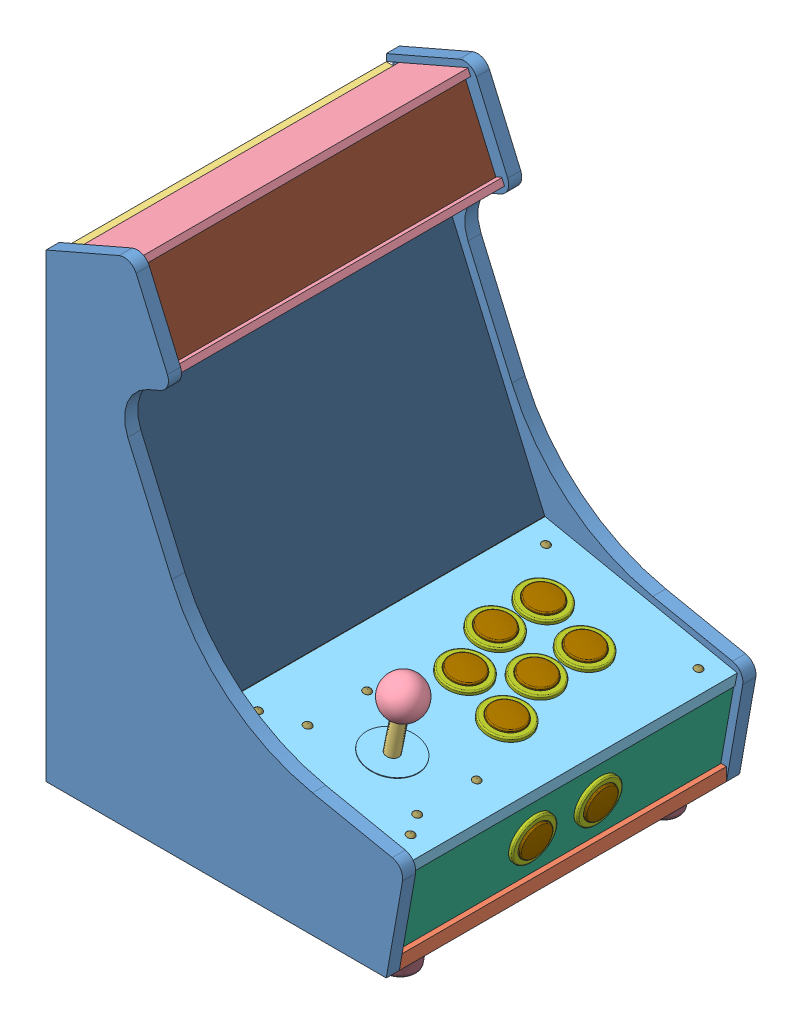
SolidWorks assembly BarTop - Ensamblaje Base, configuration Predeterminado. Lengths in mm.
Overall size (282.71 397.01 270).
106 component instances, 38 part files, 132 mates.
Components (placement in the parent):
- BarTop - Perfil v1.0-1: BarTop - Perfil v1.0 [Derecha] at (-132.2405 -179.0769 376.8453) size (272.57 376.85 10)
- BarTop - Perfil v1.0-2: BarTop - Perfil v1.0 [Izquierda] at (-132.2405 -179.0769 636.8453) size (272.57 376.85 10)
- BarTop - Base v1.0-2: BarTop - Base v1.0 [Predeterminado] at (-2.2405 -179.0769 511.8453) x (0 0 -1) z (1 0 0) size (250 10 260)
- BarTop - Trasera v1.0-1: BarTop - Trasera v1.0 [Predeterminado] at (-132.2405 -0.8669 511.8453) x (0 0 -1) z (1 0 0) size (250 336.42 10)
- BarTop - Top01 v1.0-1: BarTop - Top01 v1.0 [Top] at (-99.2135 181.6383 516.6589) x (0.917317 0.398157 0) z (0.398157 -0.917317 0) size (57.92 260 5)
- BarTop - Top01 v1.0-2: BarTop - Top01 v1.0 [Botton] at (-73.3333 122.0127 516.6589) x (0.917317 0.398157 0) z (0.398157 -0.917317 0) size (76.43 260 5)
- BarTop - Top Mando v1.0-1: BarTop - Top Mando v1.0 [Predeterminado] at (60.6117 -97.8004 511.8453) x (0 0 -1) z (0.979796 -0.2 0) size (250 10 150)
- BarTop - Botton Mando v1.0-1: BarTop - Botton Mando v1.0 [Predeterminado] at (127.5697 -145.6008 511.6606) x (0 0 -1) z (-0.984808 0.173648 0) size (260 61.41 5)
- BarTop - Escuadra 70 v1.0-2: BarTop - Escuadra 70 v1.0 [Predeterminado] at (-122.2405 -58.1616 386.8453) x (0 1 0) z (0 0 -1) size (30 12.5 15)
- BarTop - Escuadra 70 v1.0-5: BarTop - Escuadra 70 v1.0 [Predeterminado] at (-122.2405 51.8384 636.8453) x (0 -1 0) z (0 0 1) size (30 12.5 15)
- BarTop - Escuadra Mando v1.0-1: BarTop - Escuadra Mando v1.0 [Predeterminado] at (5.3678 -91.6269 386.8453) x (0.979796 -0.2 0) z (0 0 1) size (39.28 37.5 27.5)
- BarTop - Marco LCD 9.7 v1.0-1: BarTop - Marco LCD 9.7 v1.0 [Predeterminado] at (-72.642 8.6662 511.8453) x (0 0 -1) z (0.917317 0.398157 0) size (259 228.59 23.87)
- BarTop - Escuadra Mando 2 v1.0-1: BarTop - Escuadra Mando 2 v1.0 [Predeterminado] at (93.082 -133.1747 386.8453) x (1 0.000655 0) z (0 0 1) size (39.11 32.51 27.42)
- BarTop - Escuadra Base 1 v1.0-1: BarTop - Escuadra Base 1 v1.0 [Predeterminado] at (118.2897 -169.0769 386.8453) size (39.34 24.62 27.07)
- BarTop - Escuadra Base 2 v1.0-1: BarTop - Escuadra Base 2 v1.0 [Predeterminado] at (-122.2405 -169.0769 386.8453) size (30 30 32.5)
- BarTop - Escuadra Top 1 v1.0-1: BarTop - Escuadra Top 1 v1.0 [Predeterminado] at (-109.3009 157.0815 386.8453) size (27.52 41.94 27.46)
- BarTop - Stand LedStrip v1.0-1: BarTop - Stand LedStrip v1.0 [Predeterminado] at (-99.3061 110.7393 511.8453) x (0 0 -1) z (0.917317 0.398157 0) size (220 35 15)
- LCD iPad-5 - 9,7' - SN-LP097QX2-1: LCD iPad-5 - 9,7' - SN-LP097QX2 [Pacman] at (-80.3476 20.3914 510.4922) x (0 0 -1) z (0.917317 0.398157 0) size (217 160 2.4)
- Joystick Sanwa -Mod JLF-TP-8YT-W 1-1: Joystick Sanwa -Mod JLF-TP-8YT-W 1 [Predeterminado] at (69.2639 -95.1778 584.9479) x (0.979796 -0.2 0) z (-0.2 -0.979796 0) size (100 66.68 104.46)
  - SANWA_JOYSTICK_3-1: SANWA_JOYSTICK_3 [Predeterminado] at origin size (100 60 1.5)
  - SSANWA_JOYSTICK_6-1: SSANWA_JOYSTICK_6 [Predeterminado] at origin size (66 60 30)
  - SANWA_JOYSTICK_2-1: SANWA_JOYSTICK_2 [Predeterminado] x (1 0 0) z (0 1 0) size (39.99 20.68 39.98)
  - SANWA_JOYSTICK_5-1: SANWA_JOYSTICK_5 [Predeterminado] at (0 0 12.592) x (1 0 0) z (0 0 -1) size (66.1 66.68 17.11)
  - GT-Y-1: GT-Y [Predeterminado] at (0 0 27.552) size (60 60 10)
  - SANWA_JOYSTICK_0-1: SANWA_JOYSTICK_0 [Predeterminado] at (0 0 7.5029) x (0.996812 -0.079782 0) z (0.079782 0.996812 0) size (10 85 10)
  - BALL-1: BALL [Predeterminado] at (0 0 -47.9539) x (0.999996 -0.002826 0) z (0.002826 0.999996 0) size (30 30 30)
  - DUSTER-1: DUSTER [Predeterminado] at (0 0 -6.2) x (-1 0 0) z (0 0 1) size (40 40 0.5)
  - E-1: E [Predeterminado] at (0 0 39.0029) x (0.999996 -0.002826 0) z (0.002826 0.999996 0) size (5.88 1.1 10)
- sanwa_button_00_asm_6-1: sanwa_button_00_asm_6 [Predeterminado] at (46.9421 -100.1132 509.0802) x (0.979796 -0.2 0) z (0 0 1) size (34 37.41 37.09)
  - sanwa_button_00_11-1: sanwa_button_00_11 [Predeterminado] at origin size (34 22.2 37.09)
  - black_00_3-1: black_00_3 [Predeterminado] at (0 5 0) x (-1 0 0) z (0 0 1) size (14 26.9 14)
  - sanwa_button_02_8-1: sanwa_button_02_8 [Predeterminado] at (0 17 0) x (0 0 -1) z (1 0 0) size (25 13.51 28.68)
- sanwa_button_00_asm_6-3: sanwa_button_00_asm_6 [Predeterminado] at (32.919 -97.2507 472.0638) x (0.979796 -0.2 0) z (0 0 1) size (34 37.41 37.09)
  - sanwa_button_00_11-1: sanwa_button_00_11 [Predeterminado] at origin size (34 22.2 37.09)
  - black_00_3-1: black_00_3 [Predeterminado] at (0 5 0) x (-1 0 0) z (0 0 1) size (14 26.9 14)
  - sanwa_button_02_8-1: sanwa_button_02_8 [Predeterminado] at (0 17 0) x (0 0 -1) z (1 0 0) size (25 13.51 28.68)
- sanwa_button_00_asm_6-4: sanwa_button_00_asm_6 [Predeterminado] at (32.919 -97.2507 435.3274) x (0.979796 -0.2 0) z (0 0 1) size (34 37.41 37.09)
  - sanwa_button_00_11-1: sanwa_button_00_11 [Predeterminado] at origin size (34 22.2 37.09)
  - black_00_3-1: black_00_3 [Predeterminado] at (0 5 0) x (-1 0 0) z (0 0 1) size (14 26.9 14)
  - sanwa_button_02_8-1: sanwa_button_02_8 [Predeterminado] at (0 17 0) x (0 0 -1) z (1 0 0) size (25 13.51 28.68)
- sanwa_button_00_asm_6-5: sanwa_button_00_asm_6 [Predeterminado] at (85.9469 -108.075 516.2161) x (0.979796 -0.2 0) z (0 0 1) size (34 37.41 37.09)
  - sanwa_button_00_11-1: sanwa_button_00_11 [Predeterminado] at origin size (34 22.2 37.09)
  - black_00_3-1: black_00_3 [Predeterminado] at (0 5 0) x (-1 0 0) z (0 0 1) size (14 26.9 14)
  - sanwa_button_02_8-1: sanwa_button_02_8 [Predeterminado] at (0 17 0) x (0 0 -1) z (1 0 0) size (25 13.51 28.68)
- sanwa_button_00_asm_6-6: sanwa_button_00_asm_6 [Predeterminado] at (72.2638 -105.2819 479.7317) x (0.979796 -0.2 0) z (0 0 1) size (34 37.41 37.09)
  - sanwa_button_00_11-1: sanwa_button_00_11 [Predeterminado] at origin size (34 22.2 37.09)
  - black_00_3-1: black_00_3 [Predeterminado] at (0 5 0) x (-1 0 0) z (0 0 1) size (14 26.9 14)
  - sanwa_button_02_8-1: sanwa_button_02_8 [Predeterminado] at (0 17 0) x (0 0 -1) z (1 0 0) size (25 13.51 28.68)
- sanwa_button_00_asm_6-7: sanwa_button_00_asm_6 [Predeterminado] at (72.2638 -105.2819 442.994) x (0.979796 -0.2 0) z (0 0 1) size (34 37.41 37.09)
  - sanwa_button_00_11-1: sanwa_button_00_11 [Predeterminado] at origin size (34 22.2 37.09)
  - black_00_3-1: black_00_3 [Predeterminado] at (0 5 0) x (-1 0 0) z (0 0 1) size (14 26.9 14)
  - sanwa_button_02_8-1: sanwa_button_02_8 [Predeterminado] at (0 17 0) x (0 0 -1) z (1 0 0) size (25 13.51 28.68)
- sanwa_button_00_asm_6-8: sanwa_button_00_asm_6 [Predeterminado] at (113.7095 -137.8242 586.8453) x (-0.173648 -0.984808 0) z (0 0 1) size (34 37.41 37.09) (hidden)
  - sanwa_button_00_11-1: sanwa_button_00_11 [Predeterminado] at origin size (34 22.2 37.09)
  - black_00_3-1: black_00_3 [Predeterminado] at (0 5 0) x (-1 0 0) z (0 0 1) size (14 26.9 14)
  - sanwa_button_02_8-1: sanwa_button_02_8 [Predeterminado] at (0 17 0) x (0 0 -1) z (1 0 0) size (25 13.51 28.68)
- sanwa_button_00_asm_6-9: sanwa_button_00_asm_6 [Predeterminado] at (113.7095 -137.8242 536.8453) x (-0.173648 -0.984808 0) z (0 0 1) size (34 37.41 37.09)
  - sanwa_button_00_11-1: sanwa_button_00_11 [Predeterminado] at origin size (34 22.2 37.09)
  - black_00_3-1: black_00_3 [Predeterminado] at (0 5 0) x (-1 0 0) z (0 0 1) size (14 26.9 14)
  - sanwa_button_02_8-1: sanwa_button_02_8 [Predeterminado] at (0 17 0) x (0 0 -1) z (1 0 0) size (25 13.51 28.68)
- sanwa_button_00_asm_6-10: sanwa_button_00_asm_6 [Predeterminado] at (113.7095 -137.8242 486.8453) x (-0.173648 -0.984808 0) z (0 0 1) size (34 37.41 37.09)
  - sanwa_button_00_11-1: sanwa_button_00_11 [Predeterminado] at origin size (34 22.2 37.09)
  - black_00_3-1: black_00_3 [Predeterminado] at (0 5 0) x (-1 0 0) z (0 0 1) size (14 26.9 14)
  - sanwa_button_02_8-1: sanwa_button_02_8 [Predeterminado] at (0 17 0) x (0 0 -1) z (1 0 0) size (25 13.51 28.68)
- sanwa_button_00_asm_6-11: sanwa_button_00_asm_6 [Predeterminado] at (113.7095 -137.8242 436.8453) x (-0.173648 -0.984808 0) z (0 0 1) size (34 37.41 37.09) (hidden)
  - sanwa_button_00_11-1: sanwa_button_00_11 [Predeterminado] at origin size (34 22.2 37.09)
  - black_00_3-1: black_00_3 [Predeterminado] at (0 5 0) x (-1 0 0) z (0 0 1) size (14 26.9 14)
  - sanwa_button_02_8-1: sanwa_button_02_8 [Predeterminado] at (0 17 0) x (0 0 -1) z (1 0 0) size (25 13.51 28.68)
- BarTop - Vidrio v1.0-1: BarTop - Vidrio v1.0 [Predeterminado] at (-52.461 17.4256 511.8453) x (0 0 -1) z (0.917317 0.398157 0) size (250 198.5 2)
- BarTop - Marquesina v1.0-1: BarTop - Marquesina v1.0 [Predeterminado] at (-62.2378 159.5328 511.8453) x (0 0 -1) z (0.917317 0.398157 0) size (260 64 2)
- Tornillo cabeza redonda M3x16-1: Tornillo cabeza redonda M3x16 [Predeterminado] at (109.0608 -113.8137 562.1979) x (0.979796 -0.2 0) z (0 0 1) size (6 17.5 6)
- Tornillo cabeza redonda M3x16-2: Tornillo cabeza redonda M3x16 [Predeterminado] at (109.0608 -113.8137 607.6979) x (0.979796 -0.2 0) z (0 0 1) size (6 17.5 6)
- Tornillo cabeza redonda M3x16-5: Tornillo cabeza redonda M3x16 [Predeterminado] at (118.1994 -115.6791 621.8453) x (0.979796 -0.2 0) z (0 0 1) size (6 17.5 6)
- Tornillo cabeza redonda M3x16-6: Tornillo cabeza redonda M3x16 [Predeterminado] at (118.1994 -115.6791 401.8453) x (-0.297762 0.06078 0.952703) z (-0.933455 0.190541 -0.303902) size (6 17.5 6)
- Tornillo cabeza redonda M3x16-7: Tornillo cabeza redonda M3x16 [Predeterminado] at (25.347 -96.7257 562.1979) x (0.979796 -0.2 0) z (0 0 1) size (6 17.5 6)
- Tornillo cabeza redonda M3x16-9: Tornillo cabeza redonda M3x16 [Predeterminado] at (1.6037 -91.8791 621.8453) x (0.979796 -0.2 0) z (0 0 1) size (6 17.5 6)
- Tornillo cabeza redonda M3x16-10: Tornillo cabeza redonda M3x16 [Predeterminado] at (1.6037 -91.8791 401.8453) x (0.979796 -0.2 0) z (0 0 1) size (6 17.5 6)
- Tornillo cabeza redonda M3x16-11: Tornillo cabeza redonda M3x16 [Predeterminado] at (25.347 -96.7257 607.6979) x (0.979796 -0.2 0) z (0 0 1) size (6 17.5 6)
- Patas de Goma-1: Patas de Goma [Predeterminado] at (104.9763 -199.0769 613.3031) size (30 20.17 30)
- Patas de Goma-2: Patas de Goma [Predeterminado] at (101.674 -199.0769 408.8359) size (30 20.17 30)
- Patas de Goma-3: Patas de Goma [Predeterminado] at (-108.4119 -199.0769 409.4186) size (30 20.17 30)
- Patas de Goma-4: Patas de Goma [Predeterminado] at (-109.83 -199.0769 613.7143) size (30 20.17 30)
- Inserto M4 FXSLB - Fixor.es-1: Inserto M4 FXSLB - Fixor.es [Predeterminado] at (108.2897 -169.0769 396.8453) x (0.999794 0 0.02028) z (0.02028 0 -0.999794) size (6.31 5.03 6.3)
- Inserto M4 FXSLB - Fixor.es-2: Inserto M4 FXSLB - Fixor.es [Predeterminado] at (-112.2405 -169.0769 396.8453) x (1 0 0) z (0 0 -1) size (6.31 5.03 6.3)
- Inserto M4 FXSLB - Fixor.es-3: Inserto M4 FXSLB - Fixor.es [Predeterminado] at (108.2897 -169.0769 626.8453) x (1 0 0) z (0 0 -1) size (6.31 5.03 6.3)
- Inserto M4 FXSLB - Fixor.es-4: Inserto M4 FXSLB - Fixor.es [Predeterminado] at (-112.2405 -169.0769 626.8453) x (1 0 0) z (0 0 -1) size (6.31 5.03 6.3)
- Inserto M4 FXSLB - Fixor.es-5: Inserto M4 FXSLB - Fixor.es [Predeterminado] at (-122.2405 -159.0769 626.8453) x (0 1 0) z (0 0 1) size (6.31 5.03 6.3)
- Inserto M4 FXSLB - Fixor.es-6: Inserto M4 FXSLB - Fixor.es [Predeterminado] at (-122.2405 -159.0769 396.8453) x (0 1 0) z (0 0 1) size (6.31 5.03 6.3)
- Inserto M4 FXSLB - Fixor.es-7: Inserto M4 FXSLB - Fixor.es [Predeterminado] at (-122.2405 -3.1616 393.0953) x (0 1 0) z (0 0 1) size (6.31 5.03 6.3)
- Inserto M4 FXSLB - Fixor.es-8: Inserto M4 FXSLB - Fixor.es [Predeterminado] at (-122.2405 -3.1616 630.5953) x (0 1 0) z (0 0 1) size (6.31 5.03 6.3)
- Inserto M4 FXSLB - Fixor.es-9: Inserto M4 FXSLB - Fixor.es [Predeterminado] at (-102.0686 104.0896 446.8453) x (0.917317 0.398157 0) z (0 0 1) size (6.31 5.03 6.3)
- Inserto M4 FXSLB - Fixor.es-10: Inserto M4 FXSLB - Fixor.es [Predeterminado] at (-102.0686 104.0896 576.8453) x (0.917317 0.398157 0) z (0 0 1) size (6.31 5.03 6.3)
- Inserto M4 FXSLB - Fixor.es-11: Inserto M4 FXSLB - Fixor.es [Predeterminado] at (-122.2405 156.1929 626.8453) x (0 1 0) z (0 0 1) size (6.31 5.03 6.3)
- Inserto M4 FXSLB - Fixor.es-13: Inserto M4 FXSLB - Fixor.es [Predeterminado] at (-122.2405 156.1929 396.8453) x (0 1 0) z (0 0 1) size (6.31 5.03 6.3)
- BarTop - Escuadra Top 1 v1.0-2: BarTop - Escuadra Top 1 v1.0 [SimetríaPredeterminado] at (-109.3009 157.0815 636.8453) size (27.52 41.94 27.46)
- BarTop - Escuadra Base 2 v1.0-3: BarTop - Escuadra Base 2 v1.0 [SimetríaPredeterminado] at (-122.2405 -169.0769 636.8453) size (30 30 32.5)
- BarTop - Escuadra Base 1 v1.0-3: BarTop - Escuadra Base 1 v1.0 [SimetríaPredeterminado] at (118.2897 -169.0769 636.8453) size (39.34 24.62 27.07)
- BarTop - Escuadra Mando 2 v1.0-3: BarTop - Escuadra Mando 2 v1.0 [SimetríaPredeterminado] at (93.082 -133.1747 636.8453) x (1 0.000655 0) z (0 0 1) size (39.11 32.51 27.42)
- BarTop - Escuadra Mando v1.0-2: BarTop - Escuadra Mando v1.0 [SimetríaPredeterminado] at (5.3678 -91.6269 636.8453) x (0.979796 -0.2 0) z (0 0 1) size (39.28 37.5 27.5)
- 40x40x10 fan cooler 5v sunon-1: 40x40x10 fan cooler 5v sunon [Default] at (-119.7405 -111.2889 521.9641) x (0 -1 0) z (0 0 1) size (51.62 11.06 51.62)
  - 40x40x10-1: 40x40x10 [Default] at (20 0 -20) x (0 0 -1) z (-1 0 0) size (44.65 10.7 40.2)
  - blade-1: blade [Default] at (20 -3.3 -20) x (-0.569127 0 0.822249) z (0.822249 0 0.569127) size (37.1 8.47 37.1)
- AC Power outlet connector-1: AC Power outlet connector [Default] at (-137.5405 -131.2889 552.1436) x (0 0 1) z (-1 0 0) size (50 22.4 26.9)
- Interruptor KCD4-201xx-1: Interruptor KCD4-201xx [Predeterminado] at (-134.2405 -130.8594 591.8776) x (0 -1 0) z (0 0 -1) size (31 26.34 25.5)
- BarTop - Soporte Enchufes Pz1 v1.0-1: BarTop - Soporte Enchufes Pz1 v1.0 [Predeterminado] at (-130.2405 -131.2268 543.4575) x (0 0 1) z (-1 0 0) size (141 56 10)
- BarTop - Soporte Enchufes Pz2 v1.0-1: BarTop - Soporte Enchufes Pz2 v1.0 [Predeterminado] at (-124.2405 -131.4003 543.4435) x (0 0 -1) z (1 0 0) size (135 50 19)
Mates (geometry in assembly coordinates):
- Coincidente1: coincident: point of BarTop - Perfil v1.0-1; point of BarTop - Base v1.0-2
- Coincidente2: coincident: point of BarTop - Perfil v1.0-2; point of BarTop - Base v1.0-2
- Coincidente3: coincident aligned: plane of BarTop - Base v1.0-2 through (-2.2405 -179.0769 511.8453) normal (0 -1 0); plane of BarTop - Perfil v1.0-2 through (-132.2405 -179.0769 646.8453) normal (0 -1 0)
- Coincidente4: coincident aligned: plane of BarTop - Base v1.0-2 through (-2.2405 -179.0769 511.8453) normal (0 -1 0); plane of BarTop - Perfil v1.0-1 through (-132.2405 -179.0769 386.8453) normal (0 -1 0)
- Coincidente10: coincident anti-aligned: plane of BarTop - Perfil v1.0-1 through (-132.2405 -179.0769 386.8453) normal (0 0 1); plane of BarTop - Escuadra 70 v1.0-2 through (-122.2405 11.8384 386.8453) normal (0 0 -1)
- Coincidente11: coincident anti-aligned: plane of BarTop - Trasera v1.0-1 through (-122.2405 -0.8669 511.8453) normal (1 0 0); plane of BarTop - Escuadra 70 v1.0-2 through (-122.2405 11.8384 386.8453) normal (-1 0 0)
- Coincidente17: coincident aligned: plane of BarTop - Perfil v1.0-1 through (-132.2405 172.7538 386.8453) normal (-1 0 0); plane of BarTop - Trasera v1.0-1 through (-132.2405 -0.8669 511.8453) normal (-1 0 0)
- Coincidente18: coincident anti-aligned: plane of BarTop - Perfil v1.0-2 through (-132.2405 -179.0769 636.8453) normal (0 0 -1); plane of BarTop - Trasera v1.0-1 through (-122.2405 167.3431 636.8453) normal (0 0 1)
- Coincidente19: coincident anti-aligned: plane of BarTop - Base v1.0-2 through (-2.2405 -169.0769 511.8453) normal (0 1 0); plane of BarTop - Trasera v1.0-1 through (-122.2405 -169.0769 636.8453) normal (0 -1 0)
- Paralelo1: parallel aligned: plane of BarTop - Perfil v1.0-2 through (-5.1037 -69.0769 646.8453) normal (0.917317 0.398157 0); plane of LCD iPad-5 - 9,7' - SN-LP097QX2-1 through (-78.3295 21.2674 510.4922) normal (0.917317 0.398157 0)
- Coincidente25: coincident anti-aligned: plane of BarTop - Perfil v1.0-2 through (-132.2405 -179.0769 636.8453) normal (0 0 -1); plane of BarTop - Base v1.0-2 through (-132.2405 -169.0769 636.8453) normal (0 0 1)
- Distancia2: distance = 5 mm aligned: plane of BarTop - Top01 v1.0-1 through (-99.2135 181.6383 516.6589) normal (-0.398157 0.917317 0); plane of BarTop - Perfil v1.0-2 through (-67.3412 200.9231 646.8453) normal (-0.398157 0.917317 0)
- Coincidente31: coincident anti-aligned: plane of BarTop - Top01 v1.0-1 through (-130.0663 162.7962 641.8453) normal (0 0 1); plane of BarTop - Perfil v1.0-2 through (-132.2405 -179.0769 641.8453) normal (0 0 -1)
- Coincidente124: coincident anti-aligned: plane of BarTop - Perfil v1.0-1 through (-67.6816 189.6559 381.8453) normal (-0.917317 -0.398157 0); plane of BarTop - Top01 v1.0-1 through (-67.7613 189.8394 641.8453) normal (0.917317 0.398157 0)
- Distancia3: distance = 5 mm aligned: plane of BarTop - Top Mando v1.0-1 through (62.6117 -88.0024 511.8453) normal (0.2 0.979796 0); plane of BarTop - Perfil v1.0-1 through (141.8656 -99.0769 386.8453) normal (0.2 0.979796 0)
- Coincidente35: coincident anti-aligned: plane of BarTop - Perfil v1.0-2 through (-132.2405 -179.0769 636.8453) normal (0 0 -1); plane of BarTop - Top Mando v1.0-1 through (-10.873 -73.0024 636.8453) normal (0 0 1)
- Distancia4: distance = 5 mm: line of BarTop - Top Mando v1.0-1 through (136.0963 -103.0024 636.8453) axis (0 0 -1); plane of BarTop - Perfil v1.0-2 through (127.7595 -179.0769 646.8453) normal (0.984808 -0.173648 0)
- Coincidente38: coincident anti-aligned: plane of BarTop - Top01 v1.0-2 through (-104.186 103.1706 641.8453) normal (0 0 1); plane of BarTop - Perfil v1.0-2 through (-132.2405 -179.0769 641.8453) normal (0 0 -1)
- Distancia5: distance = 5 mm aligned: plane of BarTop - Perfil v1.0-2 through (-81.7315 107.4662 646.8453) normal (0.398157 -0.917317 0); plane of BarTop - Top01 v1.0-2 through (-71.3425 117.4261 516.6589) normal (0.398157 -0.917317 0)
- Coincidente40: coincident aligned: plane of BarTop - Top01 v1.0-1 through (-67.7613 189.8394 641.8453) normal (0.917317 0.398157 0); plane of BarTop - Top01 v1.0-2 through (-41.881 130.2138 641.8453) normal (0.917317 0.398157 0)
- Distancia6: distance = 7 mm aligned: plane of BarTop - Vidrio v1.0-1 through (-50.6264 18.2219 511.8453) normal (0.917317 0.398157 0); plane of BarTop - Perfil v1.0-1 through (-5.1037 -69.0769 386.8453) normal (0.917317 0.398157 0)
- Coincidente42: coincident anti-aligned: plane of BarTop - Top01 v1.0-2 through (-71.3425 117.4261 516.6589) normal (0.398157 -0.917317 0); plane of BarTop - Vidrio v1.0-1 through (-90.1435 109.2657 636.8453) normal (-0.398157 0.917317 0)
- Coincidente44: coincident anti-aligned: plane of BarTop - Perfil v1.0-1 through (-132.2405 -179.0769 386.8453) normal (0 0 1); plane of BarTop - Vidrio v1.0-1 through (-90.1435 109.2657 386.8453) normal (0 0 -1)
- Coincidente45: coincident anti-aligned: plane of BarTop - Top01 v1.0-2 through (-47.6621 130.9749 381.8453) normal (-0.917317 -0.398157 0); plane of BarTop - Marquesina v1.0-1 through (-60.4031 160.3291 511.8453) normal (0.917317 0.398157 0)
- Coincidente46: coincident anti-aligned: plane of BarTop - Top01 v1.0-1 through (-98.0191 178.8864 516.6589) normal (0.398157 -0.917317 0); plane of BarTop - Marquesina v1.0-1 through (-73.1442 189.6832 641.8453) normal (-0.398157 0.917317 0)
- Coincidente47: coincident anti-aligned: plane of BarTop - Perfil v1.0-1 through (-132.2405 -179.0769 381.8453) normal (0 0 1); plane of BarTop - Marquesina v1.0-1 through (-73.1442 189.6832 381.8453) normal (0 0 -1)
- Coincidente48: coincident anti-aligned: plane of BarTop - Top Mando v1.0-1 through (60.6117 -97.8004 511.8453) normal (-0.2 -0.979796 0); plane of BarTop - Escuadra Mando v1.0-1 through (-12.873 -82.8004 411.8453) normal (0.2 0.979796 0)
- Coincidente49: coincident anti-aligned: plane of BarTop - Perfil v1.0-1 through (-132.2405 -179.0769 386.8453) normal (0 0 1); plane of BarTop - Escuadra Mando v1.0-1 through (-0.1313 -118.5668 386.8453) normal (0 0 -1)
- Concéntrica2: concentric aligned: cylinder of BarTop - Top Mando v1.0-1 through (2.8035 -86.0013 401.8453) axis (0.2 0.979796 0) radius 1.6; cylinder of BarTop - Escuadra Mando v1.0-1 through (-4.6956 -122.7392 401.8453) axis (0.2 0.979796 0) radius 2
- Distancia11: distance = 5 mm anti-aligned: plane of BarTop - Botton Mando v1.0-1 through (117.7918 -172.2597 641.8453) normal (0 0 1); plane of BarTop - Perfil v1.0-2 through (-132.2405 -179.0769 636.8453) normal (0 0 -1)
- Distancia12: distance = 6 mm aligned: plane of BarTop - Botton Mando v1.0-1 through (127.5697 -145.6008 511.6606) normal (0.984808 -0.173648 0); plane of BarTop - Perfil v1.0-2 through (127.7595 -179.0769 646.8453) normal (0.984808 -0.173648 0)
- Coincidente51: coincident: plane of BarTop - Top Mando v1.0-1 through (60.6117 -97.8004 511.8453) normal (-0.2 -0.979796 0); line of BarTop - Botton Mando v1.0-1 through (133.3791 -112.6539 641.8453) axis (0 0 -1)
- Coincidente52: coincident anti-aligned: plane of BarTop - Vidrio v1.0-1 through (-52.461 17.4256 511.8453) normal (-0.917317 -0.398157 0); plane of BarTop - Marco LCD 9.7 v1.0-1 through (-52.461 17.4256 511.8453) normal (0.917317 0.398157 0)
- Coincidente53: coincident aligned: plane of BarTop - Vidrio v1.0-1 through (-90.1435 109.2657 636.8453) normal (0 0 1); plane of BarTop - Marco LCD 9.7 v1.0-1 through (-91.9781 108.4693 636.8453) normal (0 0 1)
- Coincidente54: coincident aligned: plane of BarTop - Vidrio v1.0-1 through (-11.1093 -72.8218 636.8453) normal (0.398157 -0.917317 0); plane of BarTop - Marco LCD 9.7 v1.0-1 through (-12.9439 -73.6181 636.8453) normal (0.398157 -0.917317 0)
- Coincidente55: coincident anti-aligned: plane of LCD iPad-5 - 9,7' - SN-LP097QX2-1 through (-78.1461 21.347 510.4922) normal (0.917317 0.398157 0); plane of BarTop - Marco LCD 9.7 v1.0-1 through (-72.642 8.6662 511.8453) normal (-0.917317 -0.398157 0)
- Concéntrica3: concentric aligned: cylinder of BarTop - Top Mando v1.0-1 through (119.3992 -109.8013 401.8453) axis (0.2 0.979796 0) radius 1.6; cylinder of BarTop - Escuadra Mando 2 v1.0-1 through (113.0297 -141.0056 401.8453) axis (0.2 0.979796 0) radius 2
- Coincidente58: coincident anti-aligned: plane of BarTop - Top Mando v1.0-1 through (60.6117 -97.8004 511.8453) normal (-0.2 -0.979796 0); plane of BarTop - Escuadra Mando 2 v1.0-1 through (89.3189 -103.6602 411.8453) normal (0.2 0.979796 0)
- Coincidente59: coincident anti-aligned: plane of BarTop - Perfil v1.0-1 through (-132.2405 -179.0769 386.8453) normal (0 0 1); plane of BarTop - Escuadra Mando 2 v1.0-1 through (93.082 -133.1747 386.8453) normal (0 0 -1)
- Coincidente61: coincident anti-aligned: plane of BarTop - Base v1.0-2 through (-2.2405 -179.0769 511.8453) normal (0 -1 0); plane of Patas de Goma-4 through (-109.83 -179.0769 613.7143) normal (0 1 0)
- Coincidente62: coincident anti-aligned: plane of BarTop - Base v1.0-2 through (-2.2405 -179.0769 511.8453) normal (0 -1 0); plane of Patas de Goma-1 through (104.9763 -179.0769 613.3031) normal (0 1 0)
- Coincidente63: coincident anti-aligned: plane of BarTop - Base v1.0-2 through (-2.2405 -179.0769 511.8453) normal (0 -1 0); plane of Patas de Goma-2 through (101.674 -179.0769 408.8359) normal (0 1 0)
- Coincidente64: coincident anti-aligned: plane of BarTop - Base v1.0-2 through (-2.2405 -179.0769 511.8453) normal (0 -1 0); plane of Patas de Goma-3 through (-108.4119 -179.0769 409.4186) normal (0 1 0)
- Concéntrica6: concentric aligned: cylinder of BarTop - Escuadra Base 1 v1.0-1 through (108.2897 -144.4558 396.8453) axis (0 -1 0) radius 3; cylinder of Inserto M4 FXSLB - Fixor.es-1 through (108.2897 -224.0769 396.8453) axis (0 -1 0) radius 2.75
- Coincidente68: coincident aligned: plane of BarTop - Escuadra Base 1 v1.0-1 through (118.2897 -169.0769 411.8453) normal (0 -1 0); plane of Inserto M4 FXSLB - Fixor.es-1 through (110.2143 -169.0769 396.8843) normal (0 -1 0)
- Concéntrica7: concentric anti-aligned: circle of BarTop - Perfil v1.0-1; circle of BarTop - Escuadra Base 1 v1.0-1
- Concéntrica8: concentric anti-aligned: circle of BarTop - Perfil v1.0-1; circle of BarTop - Escuadra Base 1 v1.0-1
- Coincidente71: coincident anti-aligned: plane of BarTop - Perfil v1.0-1 through (-132.2405 -179.0769 386.8453) normal (0 0 1); plane of BarTop - Escuadra Base 1 v1.0-1 through (118.2897 -169.0769 386.8453) normal (0 0 -1)
- Coincidente72: coincident aligned: line of BarTop - Trasera v1.0-1 through (-122.2405 -169.0769 636.8453) axis (0 0 -1); line of BarTop - Escuadra Base 2 v1.0-1 through (-122.2405 -169.0769 416.8453) axis (0 0 -1)
- Coincidente73: coincident anti-aligned: line of BarTop - Base v1.0-2 through (117.5418 -169.0769 386.8453) axis (-1 0 0); line of BarTop - Escuadra Base 2 v1.0-1 through (-122.2405 -169.0769 386.8453) axis (1 0 0)
- Concéntrica9: concentric aligned: circle of BarTop - Escuadra Base 2 v1.0-1; cylinder of Inserto M4 FXSLB - Fixor.es-2 through (-112.2405 -224.0769 396.8453) axis (0 -1 0) radius 2.95
- Coincidente74: coincident aligned: plane of BarTop - Escuadra Base 2 v1.0-1 through (-122.2405 -169.0769 416.8453) normal (0 -1 0); plane of Inserto M4 FXSLB - Fixor.es-2 through (-110.3155 -169.0769 396.8453) normal (0 -1 0)
- Concéntrica12: concentric aligned: cylinder of BarTop - Escuadra Base 2 v1.0-1 through (-92.2395 -159.0769 396.8453) axis (-1 0 0) radius 3; cylinder of Inserto M4 FXSLB - Fixor.es-6 through (-177.2405 -159.0769 396.8453) axis (-1 0 0) radius 2.95
- Coincidente77: coincident aligned: plane of BarTop - Escuadra Base 2 v1.0-1 through (-122.2405 -169.0769 416.8453) normal (-1 0 0); plane of Inserto M4 FXSLB - Fixor.es-6 through (-122.2405 -157.1519 396.8453) normal (-1 0 0)
- Coincidente79: coincident aligned: plane of BarTop - Escuadra 70 v1.0-2 through (-122.2405 11.8384 386.8453) normal (0 1 0); plane of BarTop - Escuadra 70 v1.0-5 through (-122.2405 11.8384 636.8453) normal (0 1 0)
- Coincidente80: coincident anti-aligned: plane of BarTop - Perfil v1.0-2 through (-132.2405 -179.0769 636.8453) normal (0 0 -1); plane of BarTop - Escuadra 70 v1.0-5 through (-122.2405 -18.1616 636.8453) normal (0 0 1)
- Coincidente81: coincident aligned: plane of BarTop - Escuadra 70 v1.0-2 through (-122.2405 11.8384 386.8453) normal (-1 0 0); plane of BarTop - Escuadra 70 v1.0-5 through (-122.2405 -18.1616 636.8453) normal (-1 0 0)
- Concéntrica16: concentric aligned: cylinder of BarTop - Escuadra 70 v1.0-2 through (-109.7395 -3.1616 393.0953) axis (-1 0 0) radius 3; cylinder of Inserto M4 FXSLB - Fixor.es-7 through (-177.2405 -3.1616 393.0953) axis (-1 0 0) radius 2.95
- Coincidente84: coincident aligned: plane of BarTop - Escuadra 70 v1.0-2 through (-122.2405 11.8384 386.8453) normal (-1 0 0); plane of Inserto M4 FXSLB - Fixor.es-7 through (-122.2405 -1.2366 393.0953) normal (-1 0 0)
- Concéntrica17: concentric aligned: cylinder of BarTop - Escuadra 70 v1.0-5 through (-109.7395 -3.1616 630.5953) axis (-1 0 0) radius 3; cylinder of Inserto M4 FXSLB - Fixor.es-8 through (-177.2405 -3.1616 630.5953) axis (-1 0 0) radius 2.95
- Coincidente85: coincident aligned: plane of BarTop - Escuadra 70 v1.0-5 through (-122.2405 -18.1616 636.8453) normal (-1 0 0); plane of Inserto M4 FXSLB - Fixor.es-8 through (-122.2405 -1.2366 630.5953) normal (-1 0 0)
- Concéntrica20: concentric aligned: cylinder of BarTop - Marco LCD 9.7 v1.0-1 through (-100.0778 99.503 446.8453) axis (-0.398157 0.917317 0) radius 3; cylinder of Inserto M4 FXSLB - Fixor.es-9 through (-123.9673 154.542 446.8453) axis (-0.398157 0.917317 0) radius 2.95
- Coincidente88: coincident aligned: plane of BarTop - Marco LCD 9.7 v1.0-1 through (-91.9781 108.4693 636.8453) normal (-0.398157 0.917317 0); plane of Inserto M4 FXSLB - Fixor.es-9 through (-100.3028 104.8561 446.8453) normal (-0.398157 0.917317 0)
- Concéntrica21: concentric aligned: cylinder of BarTop - Marco LCD 9.7 v1.0-1 through (-100.0778 99.503 576.8453) axis (-0.398157 0.917317 0) radius 3; cylinder of Inserto M4 FXSLB - Fixor.es-10 through (-123.9673 154.542 576.8453) axis (-0.398157 0.917317 0) radius 2.95
- Coincidente89: coincident aligned: plane of BarTop - Marco LCD 9.7 v1.0-1 through (-91.9781 108.4693 636.8453) normal (-0.398157 0.917317 0); plane of Inserto M4 FXSLB - Fixor.es-10 through (-100.3028 104.8561 576.8453) normal (-0.398157 0.917317 0)
- Concéntrica22: concentric anti-aligned: circle of BarTop - Perfil v1.0-1; circle of BarTop - Escuadra 70 v1.0-2
- Coincidente90: coincident anti-aligned: plane of BarTop - Perfil v1.0-1 through (-132.2405 -179.0769 386.8453) normal (0 0 1); plane of BarTop - Escuadra Top 1 v1.0-1 through (-109.3009 157.0815 386.8453) normal (0 0 -1)
- Coincidente92: coincident anti-aligned: plane of BarTop - Top01 v1.0-1 through (-97.2228 177.0518 516.6589) normal (0.398157 -0.917317 0); plane of BarTop - Escuadra Top 1 v1.0-1 through (-94.721 178.1376 411.8453) normal (-0.398157 0.917317 0)
- Coincidente93: coincident anti-aligned: plane of BarTop - Trasera v1.0-1 through (-122.2405 -0.8669 511.8453) normal (1 0 0); plane of BarTop - Escuadra Top 1 v1.0-1 through (-122.2405 166.1929 411.8453) normal (-1 0 0)
- Concéntrica23: concentric aligned: cylinder of Inserto M4 FXSLB - Fixor.es-3 through (108.2897 -224.0769 626.8453) axis (0 -1 0) radius 2.95; cylinder of BarTop - Escuadra Base 1 v1.0-3 through (108.2897 -144.4558 626.8453) axis (0 -1 0) radius 3
- Coincidente94: coincident aligned: plane of Inserto M4 FXSLB - Fixor.es-3 through (110.2147 -169.0769 626.8453) normal (0 -1 0); plane of BarTop - Escuadra Base 1 v1.0-3 through (118.2897 -169.0769 611.8453) normal (0 -1 0)
- Concéntrica24: concentric aligned: cylinder of Inserto M4 FXSLB - Fixor.es-4 through (-112.2405 -224.0769 626.8453) axis (0 -1 0) radius 2.95; cylinder of BarTop - Escuadra Base 2 v1.0-3 through (-112.2405 -139.0759 626.8453) axis (0 -1 0) radius 3
- Coincidente95: coincident aligned: plane of Inserto M4 FXSLB - Fixor.es-4 through (-110.3155 -169.0769 626.8453) normal (0 -1 0); plane of BarTop - Escuadra Base 2 v1.0-3 through (-122.2405 -169.0769 606.8453) normal (0 -1 0)
- Concéntrica25: concentric aligned: cylinder of Inserto M4 FXSLB - Fixor.es-5 through (-177.2405 -159.0769 626.8453) axis (-1 0 0) radius 2.95; cylinder of BarTop - Escuadra Base 2 v1.0-3 through (-92.2395 -159.0769 626.8453) axis (-1 0 0) radius 3
- Coincidente96: coincident aligned: plane of Inserto M4 FXSLB - Fixor.es-5 through (-122.2405 -157.1519 626.8453) normal (-1 0 0); plane of BarTop - Escuadra Base 2 v1.0-3 through (-122.2405 -169.0769 606.8453) normal (-1 0 0)
- Concéntrica26: concentric aligned: cylinder of BarTop - Escuadra Top 1 v1.0-2 through (-94.72 156.1929 626.8453) axis (-1 0 0) radius 3; cylinder of Inserto M4 FXSLB - Fixor.es-11 through (-177.2405 156.1929 626.8453) axis (-1 0 0) radius 2.95
- Coincidente98: coincident aligned: plane of BarTop - Escuadra Top 1 v1.0-2 through (-122.2405 166.1929 611.8453) normal (-1 0 0); plane of Inserto M4 FXSLB - Fixor.es-11 through (-122.2405 158.1179 626.8453) normal (-1 0 0)
- Concéntrica27: concentric aligned: cylinder of BarTop - Escuadra Top 1 v1.0-1 through (-94.72 156.1929 396.8453) axis (-1 0 0) radius 3; cylinder of Inserto M4 FXSLB - Fixor.es-13 through (-177.2405 156.1929 396.8453) axis (-1 0 0) radius 2.75
- Coincidente99: coincident aligned: plane of BarTop - Escuadra Top 1 v1.0-1 through (-122.2405 166.1929 411.8453) normal (-1 0 0); plane of Inserto M4 FXSLB - Fixor.es-13 through (-122.2405 158.1179 396.8453) normal (-1 0 0)
- Concéntrica28: concentric anti-aligned: cylinder of BarTop - Top Mando v1.0-1 through (68.4037 -99.3919 584.9479) axis (0.2 0.979796 0) radius 12.5; cylinder of Joystick Sanwa -Mod JLF-TP-8YT-W 1-1/SANWA_JOYSTICK_0-1 through (67.7633 -102.5292 584.9479) axis (-0.2 -0.979796 0) radius 5
- Coincidente100: coincident anti-aligned: plane of BarTop - Top Mando v1.0-1 through (62.6117 -88.0024 511.8453) normal (0.2 0.979796 0); plane of Joystick Sanwa -Mod JLF-TP-8YT-W 1-1/DUSTER-1 through (70.4039 -89.593 584.9479) normal (-0.2 -0.979796 0)
- Paralelo2: parallel aligned: plane of BarTop - Top Mando v1.0-1 through (-10.873 -73.0024 636.8453) normal (0 0 1); plane of Joystick Sanwa -Mod JLF-TP-8YT-W 1-1/SANWA_JOYSTICK_5-1 through (42.619 -102.5906 611.7574) normal (0 0 1)
- Concéntrica29: concentric anti-aligned: cylinder of BarTop - Top Mando v1.0-1 through (47.9419 -95.2152 509.0802) axis (0.2 0.979796 0) radius 15.5; cylinder of sanwa_button_00_asm_6-1/sanwa_button_00_11-1 through (50.7221 -81.595 509.0802) axis (-0.2 -0.979796 0) radius 15
- Concéntrica30: concentric anti-aligned: cylinder of BarTop - Top Mando v1.0-1 through (33.9188 -92.3527 472.0638) axis (0.2 0.979796 0) radius 15.5; cylinder of sanwa_button_00_asm_6-3/sanwa_button_00_11-1 through (36.699 -78.7326 472.0638) axis (-0.2 -0.979796 0) radius 15
- Concéntrica31: concentric anti-aligned: cylinder of BarTop - Top Mando v1.0-1 through (33.9188 -92.3527 435.3274) axis (0.2 0.979796 0) radius 15.5; cylinder of sanwa_button_00_asm_6-4/sanwa_button_00_11-1 through (36.699 -78.7326 435.3274) axis (-0.2 -0.979796 0) radius 15
- Concéntrica32: concentric anti-aligned: cylinder of BarTop - Top Mando v1.0-1 through (86.9467 -103.177 516.2161) axis (0.2 0.979796 0) radius 15.5; cylinder of sanwa_button_00_asm_6-5/sanwa_button_00_11-1 through (89.7269 -89.5569 516.2161) axis (-0.2 -0.979796 0) radius 15
- Concéntrica33: concentric anti-aligned: cylinder of BarTop - Top Mando v1.0-1 through (73.2636 -100.3839 479.7317) axis (0.2 0.979796 0) radius 15.5; cylinder of sanwa_button_00_asm_6-6/sanwa_button_00_11-1 through (76.0438 -86.7638 479.7317) axis (-0.2 -0.979796 0) radius 15
- Concéntrica34: concentric anti-aligned: cylinder of BarTop - Top Mando v1.0-1 through (73.2636 -100.3839 442.994) axis (0.2 0.979796 0) radius 15.5; cylinder of sanwa_button_00_asm_6-7/sanwa_button_00_11-1 through (76.0438 -86.7638 442.994) axis (-0.2 -0.979796 0) radius 15
- Coincidente102: coincident anti-aligned: plane of BarTop - Top Mando v1.0-1 through (62.6117 -88.0024 511.8453) normal (0.2 0.979796 0); plane of sanwa_button_00_asm_6-1/sanwa_button_00_11-1 through (49.9421 -85.4162 509.0802) normal (-0.2 -0.979796 0)
- Coincidente103: coincident anti-aligned: plane of BarTop - Top Mando v1.0-1 through (62.6117 -88.0024 511.8453) normal (0.2 0.979796 0); plane of sanwa_button_00_asm_6-3/sanwa_button_00_11-1 through (35.919 -82.5538 472.0638) normal (-0.2 -0.979796 0)
- Coincidente104: coincident anti-aligned: plane of BarTop - Top Mando v1.0-1 through (62.6117 -88.0024 511.8453) normal (0.2 0.979796 0); plane of sanwa_button_00_asm_6-4/sanwa_button_00_11-1 through (35.919 -82.5538 435.3274) normal (-0.2 -0.979796 0)
- Coincidente105: coincident anti-aligned: plane of BarTop - Top Mando v1.0-1 through (62.6117 -88.0024 511.8453) normal (0.2 0.979796 0); circle of sanwa_button_00_asm_6-5/sanwa_button_00_11-1
- Coincidente106: coincident anti-aligned: plane of BarTop - Top Mando v1.0-1 through (62.6117 -88.0024 511.8453) normal (0.2 0.979796 0); plane of sanwa_button_00_asm_6-6/sanwa_button_00_11-1 through (75.2638 -90.585 479.7317) normal (-0.2 -0.979796 0)
- Coincidente107: coincident anti-aligned: plane of BarTop - Top Mando v1.0-1 through (62.6117 -88.0024 511.8453) normal (0.2 0.979796 0); circle of sanwa_button_00_asm_6-7/sanwa_button_00_11-1
- Coincidente108: coincident anti-aligned: plane of BarTop - Botton Mando v1.0-1 through (127.5697 -145.6008 511.6606) normal (0.984808 -0.173648 0); plane of sanwa_button_00_asm_6-8/sanwa_button_00_11-1 through (128.4816 -140.4289 586.8453) normal (-0.984808 0.173648 0)
- Coincidente109: coincident anti-aligned: plane of BarTop - Botton Mando v1.0-1 through (127.5697 -145.6008 511.6606) normal (0.984808 -0.173648 0); plane of sanwa_button_00_asm_6-9/sanwa_button_00_11-1 through (128.4816 -140.4289 536.8453) normal (-0.984808 0.173648 0)
- Coincidente110: coincident anti-aligned: plane of BarTop - Botton Mando v1.0-1 through (127.5697 -145.6008 511.6606) normal (0.984808 -0.173648 0); plane of sanwa_button_00_asm_6-10/sanwa_button_00_11-1 through (128.4816 -140.4289 486.8453) normal (-0.984808 0.173648 0)
- Coincidente111: coincident anti-aligned: plane of BarTop - Botton Mando v1.0-1 through (127.5697 -145.6008 511.6606) normal (0.984808 -0.173648 0); plane of sanwa_button_00_asm_6-11/sanwa_button_00_11-1 through (128.4816 -140.4289 436.8453) normal (-0.984808 0.173648 0)
- Concéntrica39: concentric anti-aligned: cylinder of BarTop - Top Mando v1.0-1 through (110.2606 -107.9359 607.6979) axis (0.2 0.979796 0) radius 1.6; cylinder of Tornillo cabeza redonda M3x16-2 through (112.2608 -98.137 607.6979) axis (-0.2 -0.979796 0) radius 1.5
- Concéntrica40: concentric anti-aligned: cylinder of BarTop - Top Mando v1.0-1 through (110.2606 -107.9359 562.1979) axis (0.2 0.979796 0) radius 1.6; cylinder of Tornillo cabeza redonda M3x16-1 through (112.2608 -98.137 562.1979) axis (-0.2 -0.979796 0) radius 1.5
- Concéntrica41: concentric anti-aligned: cylinder of BarTop - Top Mando v1.0-1 through (119.3992 -109.8013 621.8453) axis (0.2 0.979796 0) radius 1.6; cylinder of Tornillo cabeza redonda M3x16-5 through (121.3994 -100.0024 621.8453) axis (-0.2 -0.979796 0) radius 1.5
- Concéntrica42: concentric anti-aligned: cylinder of BarTop - Top Mando v1.0-1 through (26.5468 -90.8479 607.6979) axis (0.2 0.979796 0) radius 1.6; cylinder of Tornillo cabeza redonda M3x16-11 through (28.547 -81.049 607.6979) axis (-0.2 -0.979796 0) radius 1.5
- Concéntrica43: concentric anti-aligned: cylinder of BarTop - Top Mando v1.0-1 through (26.5468 -90.8479 562.1979) axis (0.2 0.979796 0) radius 1.6; cylinder of Tornillo cabeza redonda M3x16-7 through (28.547 -81.049 562.1979) axis (-0.2 -0.979796 0) radius 1.5
- Concéntrica44: concentric anti-aligned: cylinder of BarTop - Top Mando v1.0-1 through (2.8035 -86.0013 401.8453) axis (0.2 0.979796 0) radius 1.6; cylinder of Tornillo cabeza redonda M3x16-10 through (4.8037 -76.2024 401.8453) axis (-0.2 -0.979796 0) radius 1.5
- Concéntrica45: concentric anti-aligned: cylinder of BarTop - Top Mando v1.0-1 through (2.8035 -86.0013 621.8453) axis (0.2 0.979796 0) radius 1.6; cylinder of Tornillo cabeza redonda M3x16-9 through (4.8037 -76.2024 621.8453) axis (-0.2 -0.979796 0) radius 1.5
- Concéntrica46: concentric anti-aligned: cylinder of BarTop - Top Mando v1.0-1 through (119.3992 -109.8013 401.8453) axis (0.2 0.979796 0) radius 1.6; cylinder of Tornillo cabeza redonda M3x16-6 through (121.3994 -100.0024 401.8453) axis (-0.2 -0.979796 0) radius 1.5
- Coincidente112: coincident anti-aligned: plane of BarTop - Top Mando v1.0-1 through (62.6117 -88.0024 511.8453) normal (0.2 0.979796 0); plane of Tornillo cabeza redonda M3x16-2 through (112.2608 -98.137 607.6979) normal (-0.2 -0.979796 0)
- Coincidente113: coincident anti-aligned: plane of BarTop - Top Mando v1.0-1 through (62.6117 -88.0024 511.8453) normal (0.2 0.979796 0); plane of Tornillo cabeza redonda M3x16-5 through (121.3994 -100.0024 621.8453) normal (-0.2 -0.979796 0)
- Coincidente114: coincident anti-aligned: plane of BarTop - Top Mando v1.0-1 through (62.6117 -88.0024 511.8453) normal (0.2 0.979796 0); plane of Tornillo cabeza redonda M3x16-1 through (112.2608 -98.137 562.1979) normal (-0.2 -0.979796 0)
- Coincidente116: coincident anti-aligned: plane of BarTop - Top Mando v1.0-1 through (62.6117 -88.0024 511.8453) normal (0.2 0.979796 0); plane of Tornillo cabeza redonda M3x16-9 through (4.8037 -76.2024 621.8453) normal (-0.2 -0.979796 0)
- Coincidente117: coincident anti-aligned: plane of BarTop - Top Mando v1.0-1 through (62.6117 -88.0024 511.8453) normal (0.2 0.979796 0); plane of Tornillo cabeza redonda M3x16-11 through (28.547 -81.049 607.6979) normal (-0.2 -0.979796 0)
- Coincidente119: coincident anti-aligned: plane of BarTop - Top Mando v1.0-1 through (62.6117 -88.0024 511.8453) normal (0.2 0.979796 0); plane of Tornillo cabeza redonda M3x16-7 through (28.547 -81.049 562.1979) normal (-0.2 -0.979796 0)
- Coincidente120: coincident anti-aligned: plane of BarTop - Top Mando v1.0-1 through (62.6117 -88.0024 511.8453) normal (0.2 0.979796 0); plane of Tornillo cabeza redonda M3x16-10 through (4.8037 -76.2024 401.8453) normal (-0.2 -0.979796 0)
- Coincidente121: coincident anti-aligned: plane of BarTop - Top Mando v1.0-1 through (62.6117 -88.0024 511.8453) normal (0.2 0.979796 0); plane of Tornillo cabeza redonda M3x16-6 through (121.3994 -100.0024 401.8453) normal (-0.2 -0.979796 0)
- Concéntrica47: concentric aligned: cylinder of BarTop - Top01 v1.0-2 through (-101.9019 104.162 446.8453) axis (-0.398157 0.917317 0) radius 2; cylinder of BarTop - Stand LedStrip v1.0-1 through (-103.8923 108.7476 446.8453) axis (-0.398157 0.917317 0) radius 2
- Coincidente122: coincident aligned: cylinder of BarTop - Top01 v1.0-2 through (-101.9019 104.162 576.8453) axis (-0.398157 0.917317 0) radius 2; circle of BarTop - Stand LedStrip v1.0-1
- Coincidente123: coincident anti-aligned: plane of BarTop - Top01 v1.0-2 through (-73.3333 122.0127 516.6589) normal (-0.398157 0.917317 0); plane of BarTop - Stand LedStrip v1.0-1 through (-94.7195 112.7301 584.8453) normal (0.398157 -0.917317 0)
- Concéntrica48: concentric aligned: cylinder of 40x40x10 fan cooler 5v sunon-1/40x40x10-1 through (-122.7405 -115.2889 485.9641) axis (1 0 0) radius 1.65; cylinder of BarTop - Soporte Enchufes Pz1 v1.0-1 through (-134.2405 -115.2889 485.9641) axis (1 0 0) radius 1.65
- Concéntrica49: concentric aligned: cylinder of 40x40x10 fan cooler 5v sunon-1/40x40x10-1 through (-122.7405 -147.2889 517.9641) axis (1 0 0) radius 1.65; cylinder of BarTop - Soporte Enchufes Pz1 v1.0-1 through (-134.2405 -147.2889 517.9641) axis (1 0 0) radius 1.65
- Coincidente125: coincident anti-aligned: plane of 40x40x10 fan cooler 5v sunon-1/40x40x10-1 through (-130.2405 -131.2889 501.9641) normal (-1 0 0); plane of BarTop - Soporte Enchufes Pz1 v1.0-1 through (-130.2405 -131.2268 543.4575) normal (1 0 0)
- Concéntrica50: concentric anti-aligned: cylinder of AC Power outlet connector-1 through (-137.5405 -131.2889 572.1436) axis (-1 0 0) radius 1.6; cylinder of BarTop - Soporte Enchufes Pz1 v1.0-1 through (-134.2405 -131.2889 572.1436) axis (1 0 0) radius 1.6
- Concéntrica51: concentric anti-aligned: cylinder of AC Power outlet connector-1 through (-137.5405 -131.2889 532.1436) axis (-1 0 0) radius 1.6; cylinder of BarTop - Soporte Enchufes Pz1 v1.0-1 through (-134.2405 -131.2889 532.1436) axis (1 0 0) radius 1.6
- Coincidente126: coincident anti-aligned: plane of AC Power outlet connector-1 through (-134.2405 -131.2889 552.1436) normal (1 0 0); plane of BarTop - Soporte Enchufes Pz1 v1.0-1 through (-134.2405 -131.2268 543.4575) normal (-1 0 0)
- Coincidente127: coincident anti-aligned: plane of Interruptor KCD4-201xx-1 through (-135.2405 -118.3594 602.6276) normal (0 0 1); plane of BarTop - Soporte Enchufes Pz1 v1.0-1 through (-134.2405 -144.1594 602.6276) normal (0 0 -1)
- Coincidente128: coincident anti-aligned: plane of Interruptor KCD4-201xx-1 through (-135.2405 -118.3594 581.1276) normal (0 1 0); plane of BarTop - Soporte Enchufes Pz1 v1.0-1 through (-134.2405 -118.3594 602.6276) normal (0 -1 0)
- Coincidente129: coincident anti-aligned: plane of Interruptor KCD4-201xx-1 through (-134.2405 -130.8594 591.8776) normal (1 0 0); plane of BarTop - Soporte Enchufes Pz1 v1.0-1 through (-134.2405 -131.2268 543.4575) normal (-1 0 0)
- Concéntrica52: concentric anti-aligned: cylinder of BarTop - Soporte Enchufes Pz1 v1.0-1 through (-124.2405 -109.0389 608.4559) axis (-1 0 0) radius 0.85; cylinder of BarTop - Soporte Enchufes Pz2 v1.0-1 through (-117.2405 -109.0389 608.4559) axis (1 0 0) radius 1.75
- Concéntrica53: concentric anti-aligned: cylinder of BarTop - Soporte Enchufes Pz1 v1.0-1 through (-124.2405 -153.5389 478.9559) axis (-1 0 0) radius 0.85; cylinder of BarTop - Soporte Enchufes Pz2 v1.0-1 through (-117.2405 -153.5389 478.9559) axis (1 0 0) radius 1.75
- Coincidente130: coincident anti-aligned: plane of BarTop - Soporte Enchufes Pz1 v1.0-1 through (-124.2405 -131.2268 543.4575) normal (1 0 0); plane of BarTop - Soporte Enchufes Pz2 v1.0-1 through (-124.2405 -131.4003 543.4435) normal (-1 0 0)
- Coincidente131: coincident anti-aligned: plane of BarTop - Trasera v1.0-1 through (-122.2395 -106.2889 611.2059) normal (0 0 -1); plane of BarTop - Soporte Enchufes Pz1 v1.0-1 through (-134.2405 -156.2889 611.2059) normal (0 0 1)
- Coincidente132: coincident anti-aligned: plane of BarTop - Trasera v1.0-1 through (-122.2395 -106.2889 476.2059) normal (0 -1 0); plane of BarTop - Soporte Enchufes Pz2 v1.0-1 through (-109.2405 -106.2889 476.2059) normal (0 1 0)
- Coincidente133: coincident anti-aligned: plane of BarTop - Trasera v1.0-1 through (-132.2405 -0.8669 511.8453) normal (-1 0 0); plane of BarTop - Soporte Enchufes Pz1 v1.0-1 through (-132.2405 -106.2889 611.2059) normal (1 0 0)
